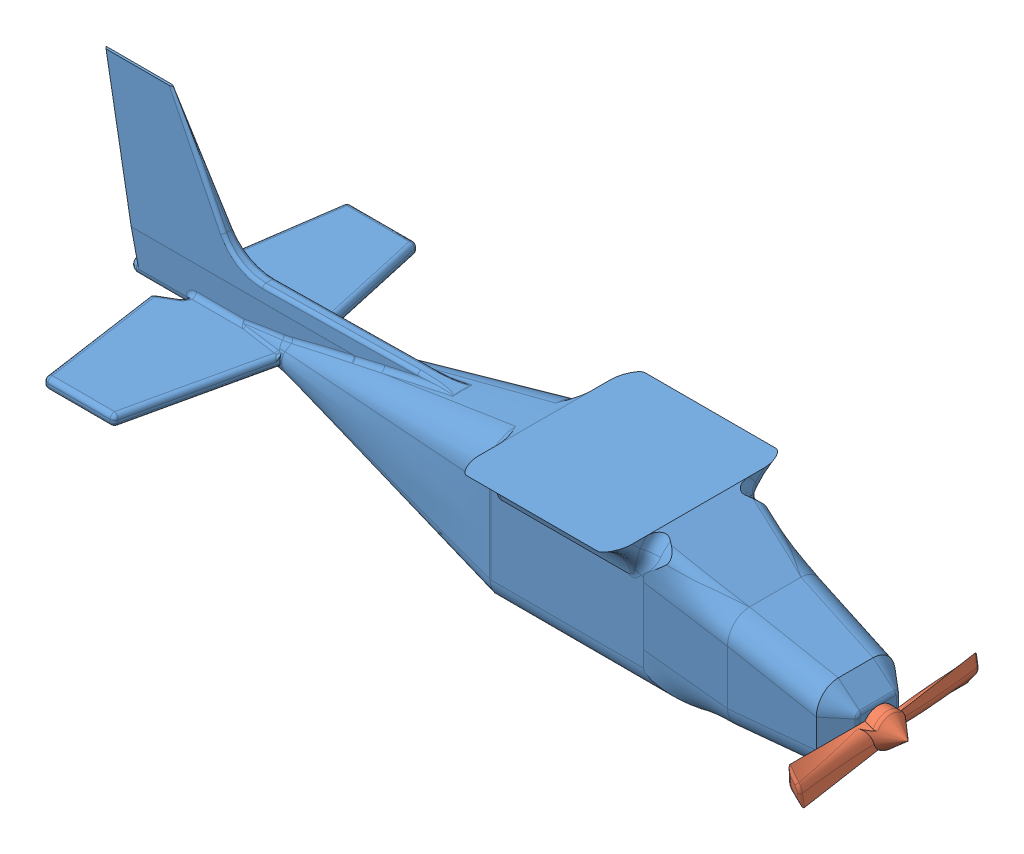
SolidWorks assembly Assembly, configuration Default. Lengths in mm.
Overall size (9004.81 2655.37 3403.6).
2 component instances, 2 part files, 3 mates.
Components (placement in the parent):
- Body-1: Body [Default] at (933.2433 1228.3717 1342.9158) size (8674.66 2655.37 3403.6)
- PropPropper-2: PropPropper [Default] at (1187.2433 1645.9032 900.4478) x (0 0 -1) z (1 0 0) size (2048.16 562.64 457.2)
Mates (geometry in assembly coordinates):
- Parallel1: parallel anti-aligned: plane of Body-1 through (933.2433 1228.3717 457.9798) normal (0 -1 0)
- Concentric2: concentric anti-aligned: cylinder of Body-1 through (1187.2433 1645.9032 900.4478) axis (-1 0 0) radius 12.7; cylinder of PropPropper-2 through (1060.2433 1645.9032 900.4478) axis (1 0 0) radius 25.4
- Coincident2: coincident anti-aligned: plane of Body-1 through (1187.2433 1645.9032 900.4478) normal (1 0 0); plane of PropPropper-2 through (1187.2433 1645.9032 900.4478) normal (-1 0 0)
